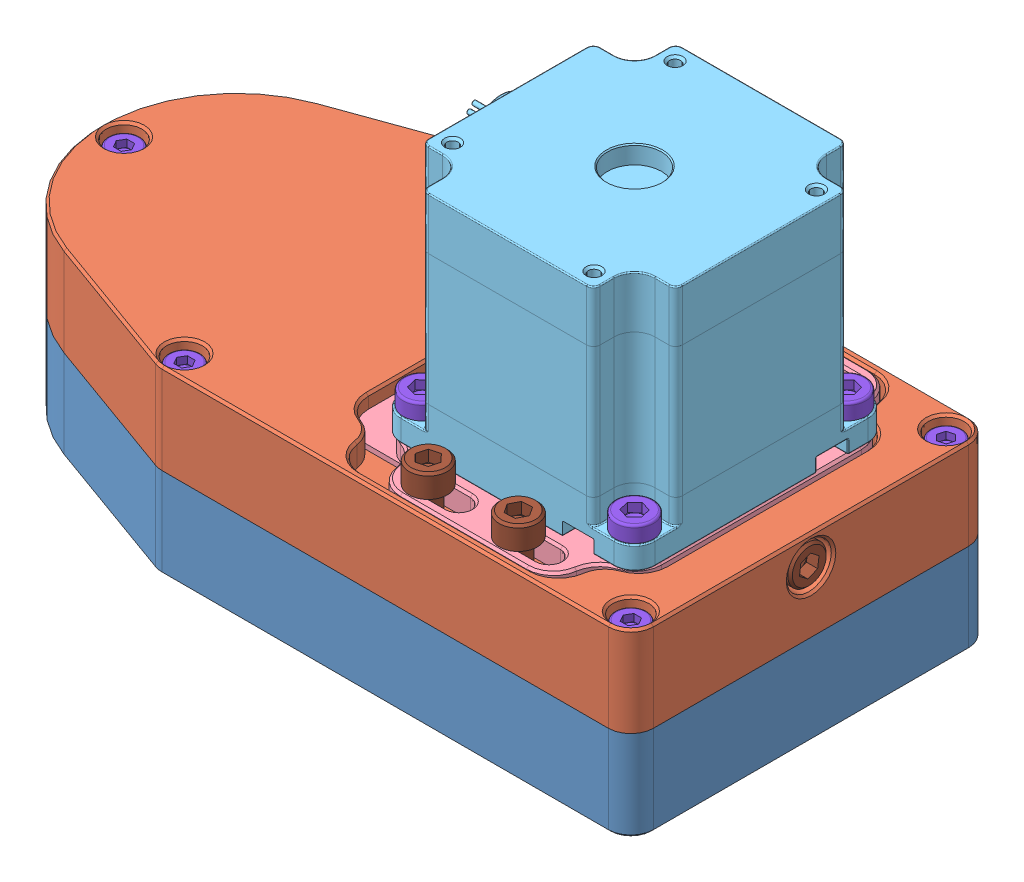
SolidWorks assembly Z Axis Motor Module, configuration Défaut. Lengths in mm.
Overall size (157.5 102 80).
25 component instances, 11 part files, 58 mates.
Components (placement in the parent):
- Z Axis Motor Module Bot-1: Z Axis Motor Module Bot [Défaut] at (52.5 0 0) size (157.5 20 80)
- Z Axis Motor Module Top-1: Z Axis Motor Module Top [Défaut] at (52.5 20 0) x (1 0 0) z (0 1 0) size (157.5 80 20)
- Z Axis Pulley 17XL037-1: Z Axis Pulley 17XL037 [Default] at (0 26 0) x (0 -1 0) z (-0.435877 0 0.900006) size (16 32 32)
- Tendeur Moteur-1: Tendeur Moteur [Défaut] at (88.3 30 0) x (0 0 -1) z (0 1 0) size (76 68.2 10)
- NEMA23 Stepper Motor-1: NEMA23 Stepper Motor [57BYGH201] at (88.3 40 0) x (0 0 1) z (0 -1 0) size (56.69 64.04 72)
- Motor Pulley 17XL037 6.35mm Bore-1: Motor Pulley 17XL037 6.35mm Bore [Default] at (88.3 14 0) x (0 1 0) z (0.510058 0 -0.86014) size (19 32 32)
- Bearing 6001-1: Bearing 6001 [Défaut] at (0 3 0) x (0 1 0) z (0.954368 0 -0.298632) size (8 28 28)
- socket thin pilot cap screw_din-3: socket thin pilot cap screw_din [DIN 6912 - M4 x 25 --- 14N] at (122.5 38.4 -35) x (0 -1 0) z (-0.257509 0 -0.966276) size (27.8 7 7)
- socket thin pilot cap screw_din-4: socket thin pilot cap screw_din [DIN 6912 - M4 x 25 --- 14N] at (122.5 38.4 35) x (0 -1 0) z (0 0 1) size (27.8 7 7)
- socket thin pilot cap screw_din-5: socket thin pilot cap screw_din [DIN 6912 - M4 x 25 --- 14N] at (23.3737 38.4 -35) x (0 -1 0) z (0 0 1) size (27.8 7 7)
- socket thin pilot cap screw_din-6: socket thin pilot cap screw_din [DIN 6912 - M4 x 25 --- 14N] at (23.3737 38.4 35) x (0 -1 0) z (0 0 1) size (27.8 7 7)
- socket thin pilot cap screw_din-7: socket thin pilot cap screw_din [DIN 6912 - M4 x 25 --- 14N] at (-25 38.4 0.0498) x (0 -1 0) z (0 0 1) size (27.8 7 7)
- socket thin pilot cap screw_din-8: socket thin pilot cap screw_din [DIN 6912 - M5 x 12 --- 7.8N] at (111.87 48.5 -23.57) x (0 -1 0) z (-0.26256 0 0.964916) size (15.5 8.5 8.5)
- socket thin pilot cap screw_din-9: socket thin pilot cap screw_din [DIN 6912 - M5 x 12 --- 7.8N] at (64.73 48.5 23.57) x (0 -1 0) z (-0.97182 0 0.235726) size (15.5 8.5 8.5)
- socket thin pilot cap screw_din-10: socket thin pilot cap screw_din [DIN 6912 - M5 x 12 --- 7.8N] at (64.73 48.5 -23.57) x (0 -1 0) z (-0.26256 0 0.964916) size (15.5 8.5 8.5)
- socket thin pilot cap screw_din-11: socket thin pilot cap screw_din [DIN 6912 - M5 x 12 --- 7.8N] at (111.87 48.5 23.57) x (0 -1 0) z (-0.281432 0 0.959581) size (15.5 8.5 8.5)
- socket thin pilot cap screw_din-14: socket thin pilot cap screw_din [DIN 6912 - M8 x 20 --- 13N] at (52.5 14 0) x (0 -1 0) z (0 0 1) size (25 13 13)
- Wedge 3x3x14-1: Wedge 3x3x14 [Défaut] at (3.15 20 1.5256) x (0 1 0) z (0.900006 0 0.435877) size (14 3 3)
- Motor Module Washer-1: Motor Module Washer [Défaut] at (0 27 0) x (1 0 0) z (0 1 0) size (21 21 2)
- socket head cap screw_am-1: socket head cap screw_am [B18.3.1M - 5 x 0.8 x 10 Hex SHCS -- 10NHX] at (127.1 33.5 0) x (-1 0 0) z (0 0.924225 0.381849) size (15 8.5 8.5)
- socket head cap screw_am-2: socket head cap screw_am [B18.3.1M - 5 x 0.8 x 10 Hex SHCS -- 10NHX] at (95.5 45 33) x (0 -1 0) z (0.058232 0 0.998303) size (15 8.5 8.5)
- socket head cap screw_am-3: socket head cap screw_am [B18.3.1M - 5 x 0.8 x 10 Hex SHCS -- 10NHX] at (75.5 45 33) x (0 -1 0) z (-0.70941 0 0.704796) size (15 8.5 8.5)
- socket head cap screw_am-4: socket head cap screw_am [B18.3.1M - 5 x 0.8 x 10 Hex SHCS -- 10NHX] at (95.5 45 -33) x (0 -1 0) z (-0.619556 0 0.784952) size (15 8.5 8.5)
- socket head cap screw_am-5: socket head cap screw_am [B18.3.1M - 5 x 0.8 x 10 Hex SHCS -- 10NHX] at (75.5 45 -33) x (0 -1 0) z (-0.823916 0 0.566712) size (15 8.5 8.5)
- socket head cap screw_am-6: socket head cap screw_am [B18.3.1M - 4 x 0.7 x 16 Hex SHCS -- 16NHX] at (0 33 0) x (0 -1 0) z (0.26018 0 0.96556) size (20 7 7)
Mates (geometry in assembly coordinates):
- Distance1: distance = 52.5 mm aligned: plane of Z Axis Motor Module Bot-1 through (52.5 0 0) normal (1 0 0); plane of assembly through (0 0 0) normal (1 0 0)
- Coïncidente2: coincident aligned: plane of Z Axis Motor Module Bot-1 through (52.5 0 0) normal (0 0 1); plane of assembly through (0 0 0) normal (0 0 1)
- Coïncidente3: coincident aligned: plane of Z Axis Motor Module Bot-1 through (52.5 0 0) normal (0 1 0); plane of assembly through (0 0 0) normal (0 1 0)
- Coaxiale1: concentric aligned: cylinder of Z Axis Motor Module Bot-1 through (0 20 0) axis (0 -1 0) radius 30; cylinder of Z Axis Motor Module Top-1 through (0 40 0) axis (0 -1 0) radius 30
- Coïncidente4: coincident anti-aligned: plane of Z Axis Motor Module Bot-1 through (52.5 20 0) normal (0 1 0); plane of Z Axis Motor Module Top-1 through (0 20 0) normal (0 -1 0)
- Coïncidente5: coincident aligned: plane of Z Axis Motor Module Bot-1 through (127.5 20 0) normal (1 0 0); plane of Z Axis Motor Module Top-1 through (127.5 40 -40) normal (1 0 0)
- Coïncidente6: coincident anti-aligned: plane of Z Axis Motor Module Top-1 through (52.5 35 0) normal (0 1 0); plane of Tendeur Moteur-1 through (88.3 35 0) normal (0 -1 0)
- Largeur1: width anti-aligned: plane of Z Axis Motor Module Top-1 through (52.5 35 -38.1) normal (0 0 1); plane of Tendeur Moteur-1 through (52.5 35 38.1) normal (0 0 -1); plane of Z Axis Motor Module Top-1 through (108.3 40 -38) normal (0 0 -1); plane of Tendeur Moteur-1 through (108.3 40 38) normal (0 0 1)
- Coïncidente7: coincident anti-aligned: plane of Tendeur Moteur-1 through (88.3 40 0) normal (0 1 0); plane of ? through (56.6786 40 -28.2) normal (0 -1 0)
- Coaxiale2: concentric anti-aligned: cylinder of Tendeur Moteur-1 through (64.73 40 23.57) axis (0 1 0) radius 2.1; cylinder of ? through (61.3086 96.001 23.57) axis (0 -1 0) radius 2.5
- Coaxiale3: concentric anti-aligned: cylinder of Tendeur Moteur-1 through (111.87 40 23.57) axis (0 1 0) radius 2.1; cylinder of ? through (108.4486 96.001 23.57) axis (0 -1 0) radius 2.5
- Coïncidente8: coincident anti-aligned: plane of Tendeur Moteur-1 through (88.3 40 0) normal (0 1 0); plane of NEMA23 Stepper Motor-1 through (88.3 40 0) normal (0 -1 0)
- Coaxiale4: concentric anti-aligned: cylinder of Tendeur Moteur-1 through (64.73 40 23.57) axis (0 1 0) radius 2.1; cylinder of NEMA23 Stepper Motor-1 through (64.73 40 23.57) axis (0 -1 0) radius 2.5
- Coaxiale5: concentric anti-aligned: cylinder of Tendeur Moteur-1 through (111.87 40 23.57) axis (0 1 0) radius 2.1; cylinder of NEMA23 Stepper Motor-1 through (111.87 40 23.57) axis (0 -1 0) radius 2.5
- Coaxiale6: concentric anti-aligned: cylinder of Z Axis Motor Module Bot-1 through (0 -39.598 0) axis (0 1 0) radius 14; cylinder of Bearing 6001-1 through (0 3 0) axis (0 -1 0) radius 14
- Coïncidente9: coincident anti-aligned: plane of Z Axis Motor Module Bot-1 through (52.5 3 0) normal (0 1 0); plane of Bearing 6001-1 through (3.6911 3 11.796) normal (0 -1 0)
- Coaxiale7: concentric aligned: cylinder of NEMA23 Stepper Motor-1 through (88.3 19 0) axis (0 1 0) radius 3.175; cylinder of Motor Pulley 17XL037 6.35mm Bore-1 through (88.3 13 0) axis (0 1 0) radius 3.175
- Coaxiale8: concentric aligned: cylinder of Z Axis Pulley 17XL037-1 through (0 27 0) axis (0 -1 0) radius 5; cylinder of Bearing 6001-1 through (0 3 0) axis (0 -1 0) radius 6
- Coïncidente10: coincident anti-aligned: plane of Z Axis Pulley 17XL037-1 through (0 11 0) normal (0 -1 0); plane of Bearing 6001-1 through (1.8814 11 6.0125) normal (0 1 0)
- Coïncidente11: coincident aligned: plane of Z Axis Pulley 17XL037-1 through (0 27 0) normal (0 1 0); plane of Motor Pulley 17XL037 6.35mm Bore-1 through (88.3 27 0) normal (0 1 0)
- Distance2: distance = 1 mm anti-aligned: plane of Tendeur Moteur-1 through (116.5 40 -28.2) normal (1 0 0); plane of Z Axis Motor Module Top-1 through (117.5 35 0) normal (-1 0 0)
- Coaxiale16: concentric aligned: cylinder of Z Axis Motor Module Top-1 through (122.5 40 -35) axis (0 1 0) radius 2.25; cylinder of socket thin pilot cap screw_din-3 through (122.5 70.15 -35) axis (0 1 0) radius 3.5
- Coïncidente19: coincident anti-aligned: plane of Z Axis Motor Module Top-1 through (124.75 35.6 -35) normal (0 1 0); plane of socket thin pilot cap screw_din-3 through (119.118 35.6 -34.0987) normal (0 -1 0)
- Coaxiale17: concentric aligned: cylinder of Z Axis Motor Module Top-1 through (122.5 40 35) axis (0 1 0) radius 2.25; cylinder of socket thin pilot cap screw_din-4 through (122.5 70.15 35) axis (0 1 0) radius 3.5
- Coïncidente20: coincident anti-aligned: plane of Z Axis Motor Module Top-1 through (124.75 35.6 35) normal (0 1 0); plane of socket thin pilot cap screw_din-4 through (126 35.6 35) normal (0 -1 0)
- Coaxiale18: concentric aligned: cylinder of Z Axis Motor Module Top-1 through (23.3737 40 -35) axis (0 1 0) radius 2.25; cylinder of socket thin pilot cap screw_din-5 through (23.3737 70.15 -35) axis (0 1 0) radius 3.5
- Coïncidente21: coincident anti-aligned: plane of Z Axis Motor Module Top-1 through (25.6237 35.6 -35) normal (0 1 0); plane of socket thin pilot cap screw_din-5 through (26.8737 35.6 -35) normal (0 -1 0)
- Coaxiale19: concentric aligned: cylinder of Z Axis Motor Module Top-1 through (23.3737 40 35) axis (0 1 0) radius 4; cylinder of socket thin pilot cap screw_din-6 through (23.3737 70.15 35) axis (0 1 0) radius 3.5
- Coïncidente22: coincident anti-aligned: plane of Z Axis Motor Module Top-1 through (25.6237 35.6 35) normal (0 1 0); plane of socket thin pilot cap screw_din-6 through (26.8737 35.6 35) normal (0 -1 0)
- Coaxiale20: concentric aligned: cylinder of Z Axis Motor Module Top-1 through (-25 40 0.0498) axis (0 1 0) radius 4; cylinder of socket thin pilot cap screw_din-7 through (-25 70.15 0.0498) axis (0 1 0) radius 3.5
- Coïncidente23: coincident anti-aligned: plane of Z Axis Motor Module Top-1 through (-22.75 35.6 0.0498) normal (0 1 0); plane of socket thin pilot cap screw_din-7 through (-21.5 35.6 0.0498) normal (0 -1 0)
- Coaxiale21: concentric anti-aligned: cylinder of NEMA23 Stepper Motor-1 through (111.87 40 -23.57) axis (0 -1 0) radius 2.5; cylinder of socket thin pilot cap screw_din-8 through (111.87 80.25 -23.57) axis (0 1 0) radius 2.5
- Coïncidente24: coincident anti-aligned: plane of NEMA23 Stepper Motor-1 through (87.6 45 0) normal (0 1 0); plane of socket thin pilot cap screw_din-8 through (115.9709 45 -22.4541) normal (0 -1 0)
- Coaxiale22: concentric anti-aligned: cylinder of NEMA23 Stepper Motor-1 through (111.87 40 23.57) axis (0 -1 0) radius 2.5; cylinder of socket thin pilot cap screw_din-11 through (111.87 80.25 23.57) axis (0 1 0) radius 2.5
- Coaxiale23: concentric anti-aligned: cylinder of NEMA23 Stepper Motor-1 through (64.73 40 -23.57) axis (0 -1 0) radius 2.5; cylinder of socket thin pilot cap screw_din-10 through (64.73 80.25 -23.57) axis (0 1 0) radius 2.5
- Coaxiale24: concentric anti-aligned: cylinder of NEMA23 Stepper Motor-1 through (64.73 40 23.57) axis (0 -1 0) radius 2.5; cylinder of socket thin pilot cap screw_din-9 through (64.73 80.25 23.57) axis (0 1 0) radius 2.5
- Coïncidente25: coincident anti-aligned: plane of NEMA23 Stepper Motor-1 through (87.6 45 0) normal (0 1 0); plane of socket thin pilot cap screw_din-9 through (65.7318 45 27.7002) normal (0 -1 0)
- Coïncidente26: coincident anti-aligned: plane of NEMA23 Stepper Motor-1 through (87.6 45 0) normal (0 1 0); plane of socket thin pilot cap screw_din-11 through (115.9482 45 24.7661) normal (0 -1 0)
- Coïncidente27: coincident anti-aligned: plane of NEMA23 Stepper Motor-1 through (87.6 45 0) normal (0 1 0); plane of socket thin pilot cap screw_din-10 through (68.8309 45 -22.4541) normal (0 -1 0)
- Coaxiale26: concentric anti-aligned: cylinder of Z Axis Motor Module Bot-1 through (52.5 20 0) axis (0 -1 0) radius 4; cylinder of socket thin pilot cap screw_din-14 through (52.5 45.75 0) axis (0 1 0) radius 4
- Coïncidente29: coincident anti-aligned: plane of Z Axis Motor Module Bot-1 through (52.5 9 0) normal (0 1 0); plane of socket thin pilot cap screw_din-14 through (59 9 0) normal (0 -1 0)
- Coïncidente30: coincident anti-aligned: plane of Z Axis Pulley 17XL037-1 through (5.1962 27 4.1832) normal (-0.900006 0 -0.435877); plane of Wedge 3x3x14-1 through (5.85 14.5 2.8332) normal (0.900006 0 0.435877)
- Coïncidente31: coincident anti-aligned: plane of Z Axis Pulley 17XL037-1 through (5.1962 27 4.1832) normal (0.435877 0 -0.900006); plane of Wedge 3x3x14-1 through (5.1962 14.5 4.1832) normal (-0.435877 0 0.900006)
- Tangent1: tangent aligned: plane of Z Axis Pulley 17XL037-1 through (0 27 0) normal (0 1 0); cylinder of Wedge 3x3x14-1 through (5.85 25.5 2.8332) axis (-0.900006 0 -0.435877) radius 1.5
- Coïncidente32: coincident anti-aligned: plane of Z Axis Pulley 17XL037-1 through (0 27 0) normal (0 1 0); plane of Motor Module Washer-1 through (0 27 0) normal (0 -1 0)
- Coaxiale27: concentric aligned: cylinder of Z Axis Pulley 17XL037-1 through (0 27 0) axis (0 -1 0) radius 5; cylinder of Motor Module Washer-1 through (0 29 0) axis (0 -1 0) radius 10.5
- Coaxiale28: concentric aligned: cylinder of Z Axis Motor Module Top-1 through (127.5 33.5 0) axis (1 0 0) radius 2.75; cylinder of socket head cap screw_am-1 through (158.85 33.5 0) axis (1 0 0) radius 4.25
- Coïncidente33: coincident anti-aligned: plane of Z Axis Motor Module Top-1 through (122.1 33.5 -2.75) normal (1 0 0); plane of socket head cap screw_am-1 through (122.1 31.8771 3.928) normal (-1 0 0)
- Coaxiale29: concentric aligned: cylinder of Z Axis Motor Module Top-1 through (95.5 35 33) axis (0 1 0) radius 2.1; cylinder of socket head cap screw_am-2 through (95.5 76.75 33) axis (0 1 0) radius 4.25
- Coaxiale30: concentric aligned: cylinder of Z Axis Motor Module Top-1 through (75.5 35 33) axis (0 1 0) radius 2.1; cylinder of socket head cap screw_am-3 through (75.5 76.75 33) axis (0 1 0) radius 4.25
- Coaxiale31: concentric aligned: cylinder of Z Axis Motor Module Top-1 through (95.5 35 -33) axis (0 1 0) radius 2.1; cylinder of socket head cap screw_am-4 through (95.5 76.75 -33) axis (0 1 0) radius 4.25
- Coaxiale32: concentric aligned: cylinder of Z Axis Motor Module Top-1 through (75.5 35 -33) axis (0 1 0) radius 2.1; cylinder of socket head cap screw_am-5 through (75.5 76.75 -33) axis (0 1 0) radius 4.25
- Coïncidente34: coincident anti-aligned: plane of Tendeur Moteur-1 through (88.3 40 0) normal (0 1 0); plane of socket head cap screw_am-3 through (78.4954 40 36.015) normal (0 -1 0)
- Coïncidente35: coincident anti-aligned: plane of Tendeur Moteur-1 through (88.3 40 0) normal (0 1 0); plane of socket head cap screw_am-2 through (99.7428 40 32.7525) normal (0 -1 0)
- Coïncidente36: coincident anti-aligned: plane of Tendeur Moteur-1 through (88.3 40 0) normal (0 1 0); plane of socket head cap screw_am-4 through (98.836 40 -30.3669) normal (0 -1 0)
- Coïncidente37: coincident anti-aligned: plane of Tendeur Moteur-1 through (88.3 40 0) normal (0 1 0); plane of socket head cap screw_am-5 through (77.9085 40 -29.4984) normal (0 -1 0)
- Coaxiale33: concentric anti-aligned: cylinder of Motor Module Washer-1 through (0 29 0) axis (0 -1 0) radius 2.1; cylinder of socket head cap screw_am-6 through (0 64.75 0) axis (0 1 0) radius 3.5
- Coïncidente38: coincident anti-aligned: plane of Motor Module Washer-1 through (0 29 0) normal (0 1 0); plane of socket head cap screw_am-6 through (3.3795 29 -0.9106) normal (0 -1 0)
